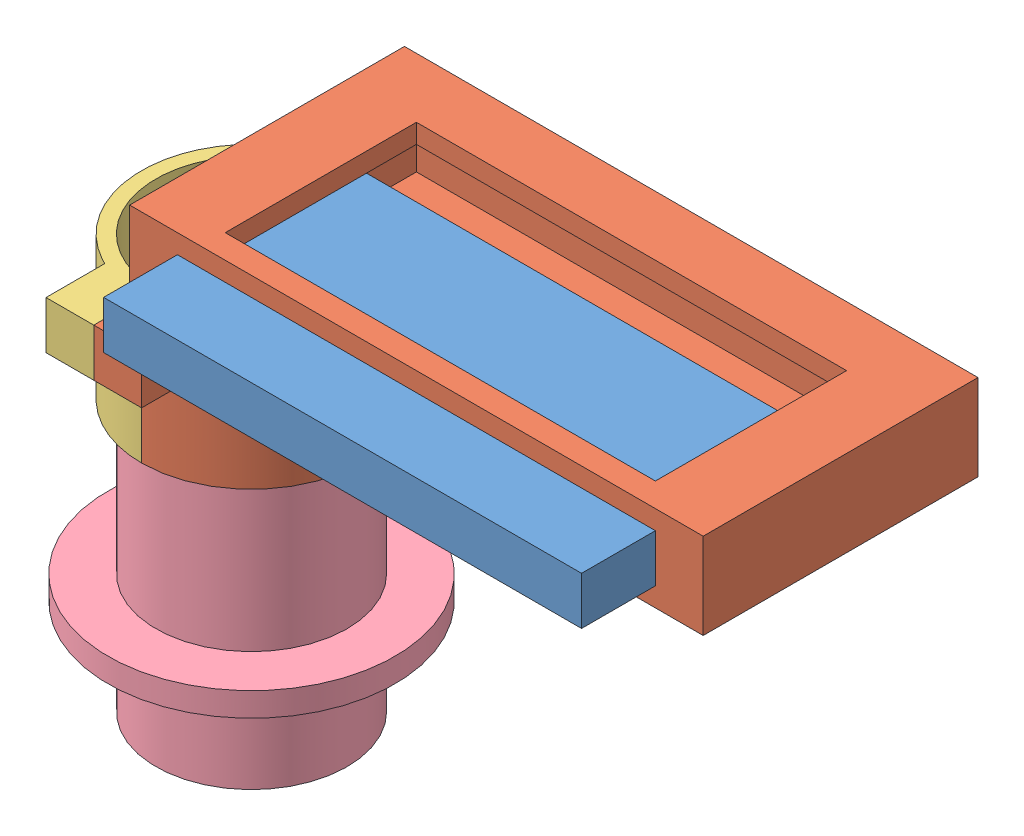
SolidWorks assembly Assem1, configuration Default. Lengths in mm.
Overall size (161.52 104.54 83.05).
4 component instances, 4 part files, 6 mates.
Components (placement in the parent):
- Scintillator-1: Scintillator [Default] at (-103.3656 51.8016 2.4473) x (1 0 0) z (0 -1 0) size (100 50 10)
- Bottom-2: Bottom [Default] at (6.6344 55.8016 -13.0008) size (120 48 65)
- Tube Bracket-2: Tube Bracket [Default] at (-113.3656 37.8016 -38.5008) x (-1 0 0) z (0 0 1) size (23 30 66)
- fibertube-1: fibertube [Default] at (-99.1337 11.2666 -29.2028) x (-0.837169 0 -0.546944) z (-0.546944 0 0.837169) size (60 60 60)
Mates (geometry in assembly coordinates):
- Coincident4: coincident anti-aligned: plane of Scintillator-1 through (-103.3656 51.8016 2.4473) normal (0 1 0); plane of Bottom-2 through (6.6344 51.8016 -13.0008) normal (0 -1 0)
- Coincident5: coincident anti-aligned: plane of Scintillator-1 through (-103.3656 41.8016 2.4473) normal (-1 0 0); plane of Bottom-2 through (-103.3656 41.8016 -13.0008) normal (1 0 0)
- Coincident8: coincident anti-aligned: plane of Bottom-2 through (-113.3656 41.8016 -13.0008) normal (-1 0 0); plane of Tube Bracket-2 through (-113.3656 7.8016 -18.5008) normal (1 0 0)
- Concentric1: concentric anti-aligned: circle of Bottom-2; circle of Tube Bracket-2
- Concentric2: concentric anti-aligned: circle of Bottom-2; circle of Tube Bracket-2
- Concentric3: concentric aligned: circle of Tube Bracket-2; circle of fibertube-1
